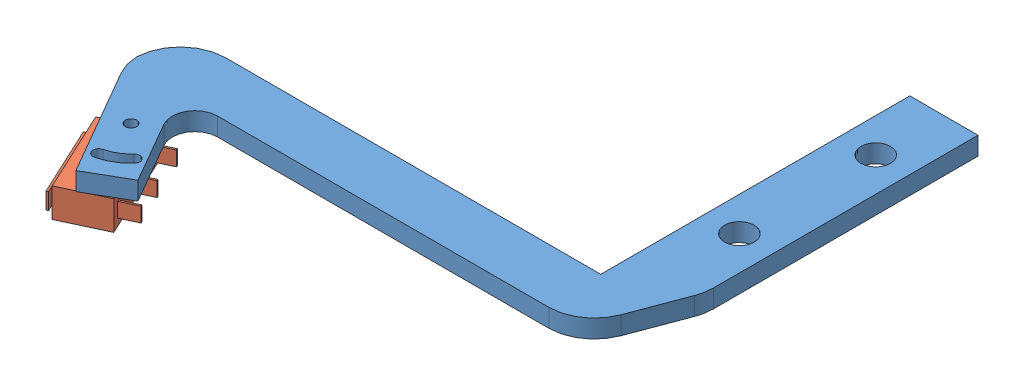
SolidWorks assembly 微動開關(SS-5GL)-固定片組合[02_v1.0(彎曲)], configuration Default. Lengths in mm.
Overall size (107.49 10.4 107.97).
2 component instances, 2 part files, 3 mates.
Components (placement in the parent):
- 微動開關(SS-5GL)固定片[02_v1.0]-1: 微動開關(SS-5GL)固定片[02_v1.0] [Default] at (-81.6875 55.4719 75.9294) size (107.49 4 105.98)
- 微動開關_SS-5GL[01-v1.0]-1: 微動開關_SS-5GL[01-v1.0] [Default] at (-6.8412 52.2719 142.3018) x (0.422618 0 0.906308) z (0.906308 0 -0.422618) size (19.8 6.4 15.2)
Mates (geometry in assembly coordinates):
- Coincident5: coincident: plane of 微動開關(SS-5GL)固定片[02_v1.0]-1 through (-81.6875 55.4719 75.9294) normal (0 -1 0); plane of 微動開關_SS-5GL[01-v1.0]-1 through (-6.8832 55.4719 142.2991) normal (0 1 0)
- Concentric6: concentric: cylinder of 微動開關(SS-5GL)固定片[02_v1.0]-1 through (-6.5134 55.4719 136.8527) axis (0 1 0) radius 1.25; cylinder of 微動開關_SS-5GL[01-v1.0]-1 through (-6.5134 55.4719 136.8527) axis (0 -1 0) radius 1.25
- Angle1: planar angle = 0.087266 rad aligned: plane of 微動開關_SS-5GL[01-v1.0]-1 through (-15.6473 49.0719 135.4847) normal (-0.906308 0 0.422618); plane of 微動開關(SS-5GL)固定片[02_v1.0]-1 through (-3.5935 59.4719 151.9101) normal (-0.866025 0 0.5)
